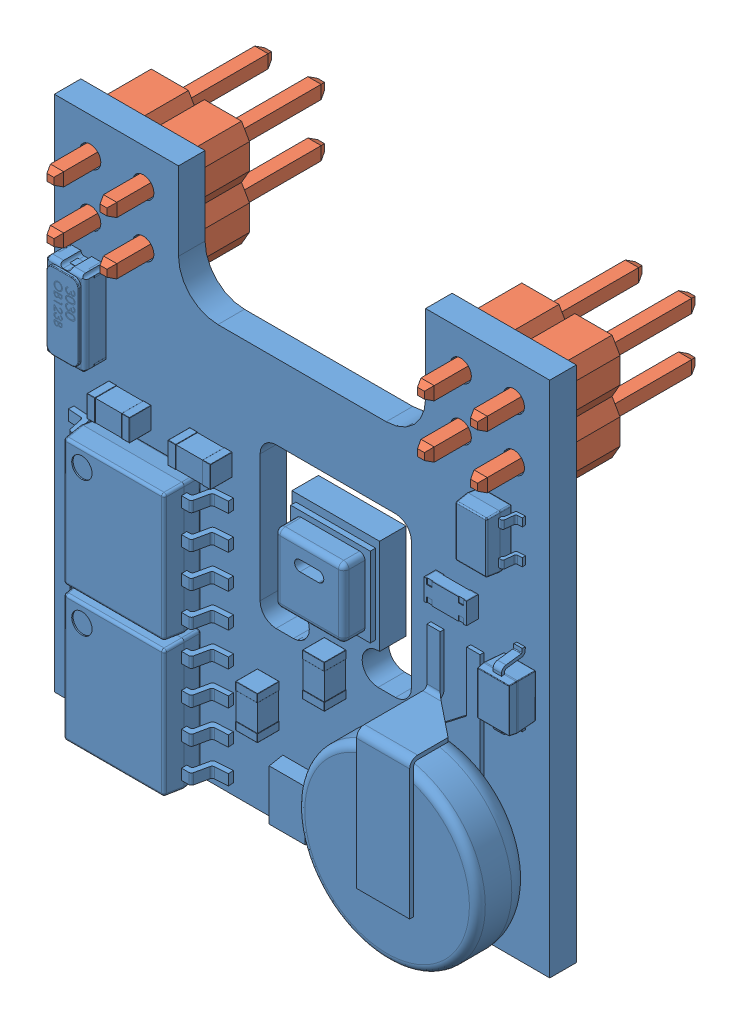
SolidWorks assembly SAU-G0-EX_AHT-GL_PCB, configuration 默认. Lengths in mm.
Overall size (18.66 19.5 9.5).
3 component instances, 2 part files, 4 mates.
Components (placement in the parent):
- SAU-G0-EX_AHT-GL_STEP_AD-1: SAU-G0-EX_AHT-GL_STEP_AD [默认] at (33.02 -15.1211 17.6394) x (-1 0 0) z (0 0 -1) size (18.66 19.5 3.8)
- 2.0mm排针2x2-1: 2.0mm排针2x2 [Default] at (-7.9796 3.4685 17.6394) x (-1 0 0) z (0 -1 0) size (4 8.2 4)
- 2.0mm排针2x2-2: 2.0mm排针2x2 [Default] at (7.9796 5.4685 17.6394) x (1 0 0) z (0 1 0) size (4 8.2 4)
Mates (geometry in assembly coordinates):
- 重合1: coincident: plane of SAU-G0-EX_AHT-GL_STEP_AD-1 through (9.332 -12.6831 17.6394) normal (0 0 -1); plane of 2.0mm排针2x2-1 through (-7.9796 3.4685 17.6394) normal (0 0 1)
- 平行1: parallel: plane of 2.0mm排针2x2-1 through (-6.9796 6.4685 15.6394) normal (0 1 0); plane of SAU-G0-EX_AHT-GL_STEP_AD-1 through (-4.654 6.8209 18.639) normal (0 1 0)
- 距离1: distance = 0.25 mm: plane of 2.0mm排针2x2-1 through (-6.2296 5.7185 20.1394) normal (0 1 0); cylinder of SAU-G0-EX_AHT-GL_STEP_AD-1 through (-5.9796 5.4685 18.639) axis (0 0 1) radius 0.4
- 距离2: distance = 0.25 mm: plane of 2.0mm排针2x2-1 through (-5.7296 5.7185 20.1394) normal (1 0 0); cylinder of SAU-G0-EX_AHT-GL_STEP_AD-1 through (-5.9796 5.4685 18.639) axis (0 0 1) radius 0.4
